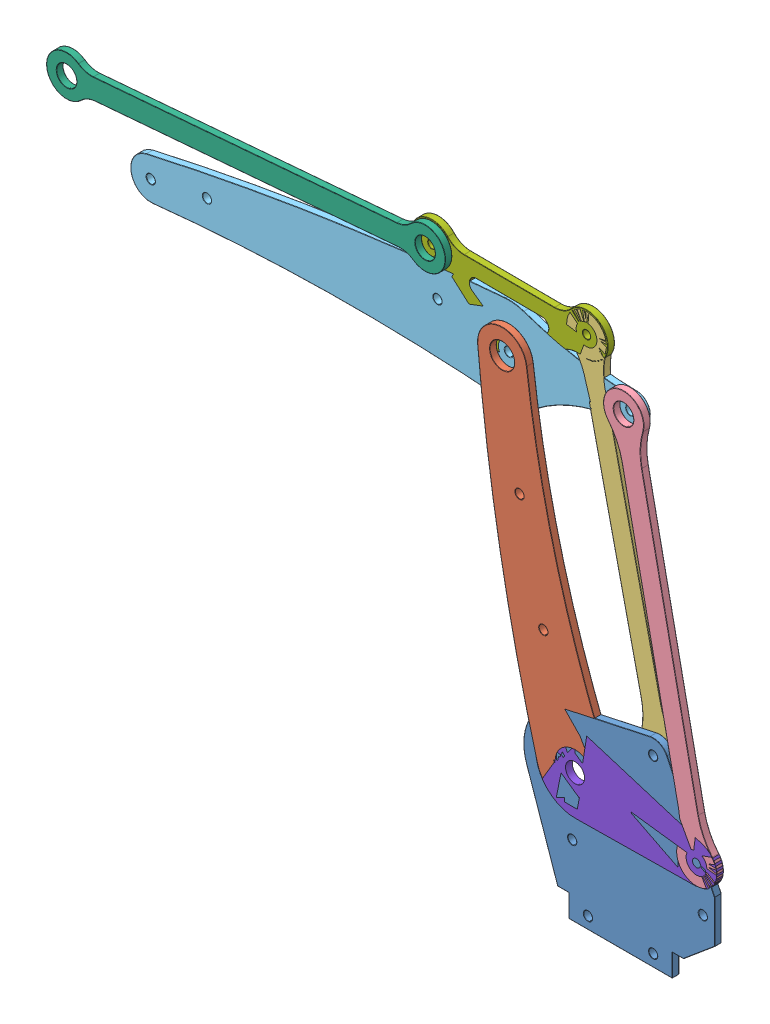
SolidWorks assembly Złożenie2, configuration Domyślna. Lengths in mm.
Overall size (309.64 235.78 6).
8 component instances, 8 part files, 32 mates.
Components (placement in the parent):
- Część2^Złożenie2-1: Część2^Złożenie2 [Domyślna] at origin size (84.94 88.29 3)
- Część1^Złożenie2-1: Część1^Złożenie2 [Domyślna] at origin size (60.95 172.9 3)
- Część3^Złożenie2-1: Część3^Złożenie2 [Domyślna] at origin size (50.62 162.36 3)
- Część4^Złożenie2-1: Część4^Złożenie2 [Domyślna] at origin size (50.45 174.68 3)
- Część5^Złożenie2-1: Część5^Złożenie2 [Domyślna] at origin size (228.28 42.13 3)
- Część6^Złożenie2-1: Część6^Złożenie2 [Domyślna] at origin size (177.44 31.37 3)
- Część7^Złożenie2-1: Część7^Złożenie2 [Domyślna] at origin size (87.81 43.3 3)
- Część8^Złożenie2-1: Część8^Złożenie2 [Domyślna] at origin size (80.5 35 3)
Mates (geometry in assembly coordinates):
- Ustalone1: in place: plane of ? through (0 0 0) normal (0 0 1); moOrthogonalPlaneRef_w of ? through (0 0 0) normal (0 1 0); plane of ? through (0 0 0) normal (1 0 0); unknown of ?
- Wspólnie1: coincident: plane of Część2^Złożenie2-1; plane of assembly
- Wspólnie2: coincident: plane of ? through (0 0 0) normal (0 1 0)
- Wspólnie3: coincident: plane of ? through (0 0 0) normal (1 0 0)
- Ustalone2: in place: plane of ? through (0 0 0) normal (0 0 1); plane of ? through (0 0 0) normal (0 1 0); plane of ? through (0 0 0) normal (1 0 0); unknown of ?
- Wspólnie1: coincident: plane of Część1^Złożenie2-1; plane of assembly
- Wspólnie2: coincident: plane of ? through (0 0 0) normal (0 1 0)
- Wspólnie3: coincident: plane of ? through (0 0 0) normal (1 0 0)
- Ustalone3: in place: plane of ? through (0 0 0) normal (0 0 1); plane of ? through (0 0 0) normal (0 1 0); plane of ? through (0 0 0) normal (1 0 0); unknown of ?
- Wspólnie1: coincident: plane of Część3^Złożenie2-1; plane of assembly
- Wspólnie2: coincident: plane of ? through (0 0 0) normal (0 1 0)
- Wspólnie3: coincident: plane of ? through (0 0 0) normal (1 0 0)
- Ustalone4: in place: plane of ? through (0 0 0) normal (0 0 1); plane of ? through (0 0 0) normal (0 1 0); plane of ? through (0 0 0) normal (1 0 0); unknown of ?
- Wspólnie1: coincident: plane of Część4^Złożenie2-1; plane of assembly
- Wspólnie2: coincident: plane of ? through (0 0 0) normal (0 1 0)
- Wspólnie3: coincident: plane of ? through (0 0 0) normal (1 0 0)
- Ustalone5: in place: plane of ? through (0 0 0) normal (0 0 1); plane of ? through (0 0 0) normal (0 1 0); plane of ? through (0 0 0) normal (1 0 0); unknown of ?
- Wspólnie1: coincident: plane of Część5^Złożenie2-1; plane of assembly
- Wspólnie2: coincident: plane of ? through (0 0 0) normal (0 1 0)
- Wspólnie3: coincident: plane of ? through (0 0 0) normal (1 0 0)
- Ustalone6: in place: plane of ? through (0 0 0) normal (0 0 1); plane of ? through (0 0 0) normal (0 1 0); plane of ? through (0 0 0) normal (1 0 0); unknown of ?
- Wspólnie1: coincident: plane of Część6^Złożenie2-1; plane of assembly
- Wspólnie2: coincident: plane of ? through (0 0 0) normal (0 1 0)
- Wspólnie3: coincident: plane of ? through (0 0 0) normal (1 0 0)
- Ustalone7: in place: plane of ? through (0 0 0) normal (0 0 1); plane of ? through (0 0 0) normal (0 1 0); plane of ? through (0 0 0) normal (1 0 0); unknown of ?
- Wspólnie1: coincident: plane of Część7^Złożenie2-1; plane of assembly
- Wspólnie2: coincident: plane of ? through (0 0 0) normal (0 1 0)
- Wspólnie3: coincident: plane of ? through (0 0 0) normal (1 0 0)
- Ustalone8: in place: plane of ? through (0 0 0) normal (0 0 1); plane of ? through (0 0 0) normal (0 1 0); plane of ? through (0 0 0) normal (1 0 0); unknown of ?
- Wspólnie1: coincident: plane of Część8^Złożenie2-1; plane of assembly
- Wspólnie2: coincident: plane of ? through (0 0 0) normal (0 1 0)
- Wspólnie3: coincident: plane of ? through (0 0 0) normal (1 0 0)
